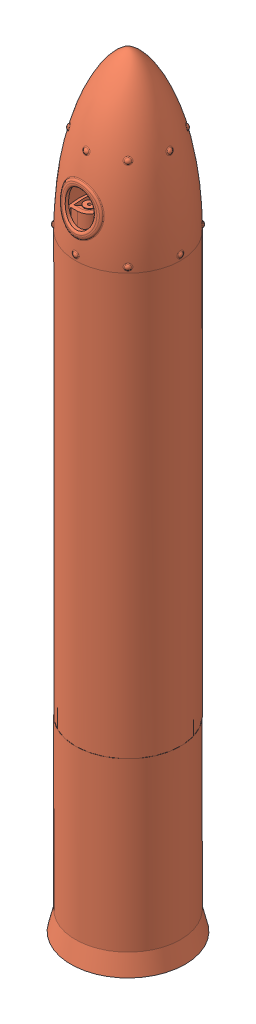
SolidWorks assembly Assem1, configuration Default. Lengths in mm.
Overall size (43.55 291 43.55).
2 component instances, 2 part files, 1 mates.
Components (placement in the parent):
- rocket nozzle for pocket rocket-1: rocket nozzle for pocket rocket [Default] at (10.1448 20.4263 92.1945) size (36 67.17 36)
- rocket outer frame-1: rocket outer frame [Default] at (10.1448 159.9223 92.1945) size (43.55 291 43.55)
Mates (geometry in assembly coordinates):
- Concentric2: concentric anti-aligned: cylinder of rocket nozzle for pocket rocket-1 through (10.1448 20.4263 92.1945) axis (0 1 0) radius 18; cylinder of rocket outer frame-1 through (10.1448 -61.0802 92.1945) axis (0 -1 0) radius 17.8049
